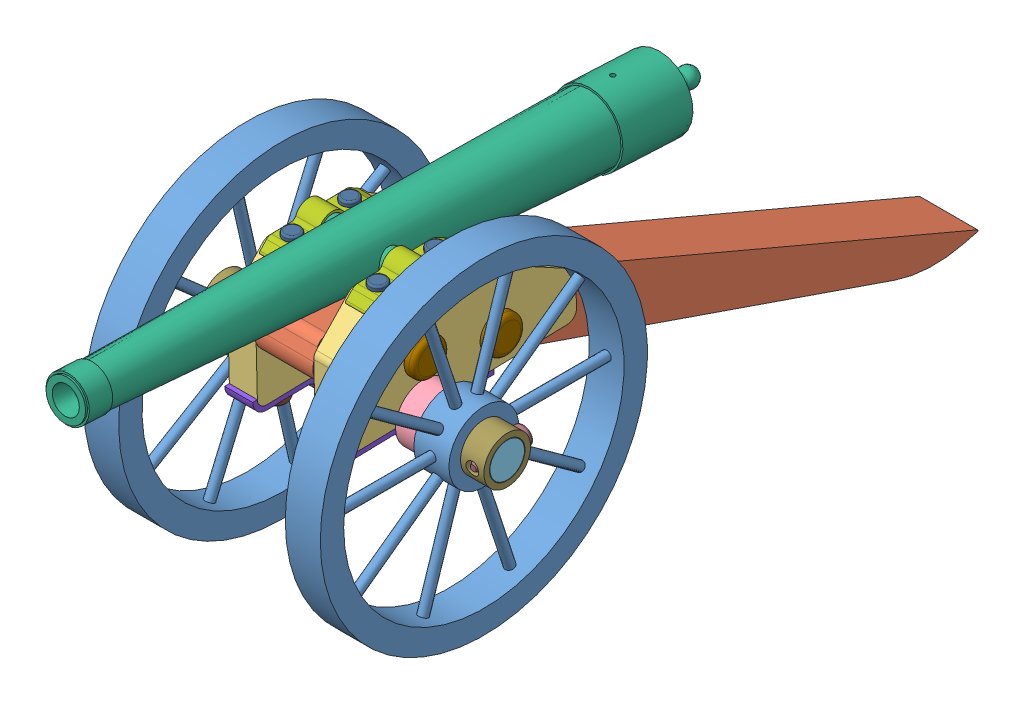
SolidWorks assembly Cannon, configuration Default. Lengths in mm.
Overall size (76.96 112.22 246.97).
32 component instances, 13 part files, 59 mates.
Components (placement in the parent):
- Wheel-1: Wheel [Default] at (68.3634 42.1628 52.5485) size (9.53 88.9 88.9)
- Wheel-2: Wheel [Default] at (13.5756 42.1628 52.5485) x (1 0 0) z (0 0.091495 0.995806) size (9.53 88.9 88.9)
- Body-1: Body [Default] at (-32.1995 -109.6773 -118.4112) x (1 0 0) z (0 0.32541 0.945573) size (30.99 51.83 194.24)
  - Tail-1: Tail [Default] at (73.3976 101.4468 142.9508) size (15.75 17.53 189.98)
  - Side-1: Side [Default] at (61.7136 98.5617 215.0109) x (-1 0 0) z (0 0.34834 -0.937368) size (7.62 31.75 63.36)
  - Side-2: Side [Default] at (85.0816 98.5617 215.0109) x (-1 0 0) z (0 0.34834 -0.937368) size (7.62 31.75 63.36)
- Shim-1: Shim [Default] at (56.7429 42.1628 52.5485) x (1 0 0) z (0 -0.052919 0.998599) size (6.35 15.24 15.24)
- Shim-2: Shim [Default] at (18.8461 42.1628 52.5485) x (1 0 0) z (0 -0.853507 -0.521081) size (6.35 15.24 15.24)
- Axle-1: Axle [Default] at (40.9949 42.1628 52.5485) x (1 0 0) z (0 -0.996928 -0.078322) size (76.96 9.4 9.4)
- Barrel-1: Barrel [Default] at (41.1981 73.9034 53.3217) x (-1 0 0) z (0 -0.049929 -0.998753) size (30.48 19.18 171.63)
- BarrelStrap-1: BarrelStrap [Default] at (52.8821 73.9034 53.3209) x (1 0 0) z (0 -0.024351 0.999703) size (6.35 6.43 27.12)
- BarrelStrap-2: BarrelStrap [Default] at (29.5141 73.9034 53.3209) x (1 0 0) z (0 -0.024351 0.999703) size (6.35 6.43 27.12)
- AxleStrap-1: AxleStrap [Default] at (29.5141 41.528 52.5328) x (1 0 0) z (0 0.024351 -0.999703) size (7.62 9.27 42.12)
- AxleStrap-2: AxleStrap [Default] at (52.8821 41.528 52.5328) x (1 0 0) z (0 0.024351 -0.999703) size (7.62 9.27 42.12)
- BodyPin-1: BodyPin [Default] at (49.7071 59.4063 67.5249) x (-1 0 0) z (0 -0.924225 -0.381849) size (16.51 9.78 9.78)
- BodyPin-2: BodyPin [Default] at (32.6891 55.8626 52.8822) size (16.51 9.78 9.78)
- BodyPin-3: BodyPin [Default] at (32.6891 59.4063 67.5249) size (16.51 9.78 9.78)
- BodyPin-4: BodyPin [Default] at (32.6891 50.8711 32.2573) size (16.51 9.78 9.78)
- BodyPin-5: BodyPin [Default] at (49.7071 55.8626 52.8822) x (-1 0 0) z (0 -0.924225 -0.381849) size (16.51 9.78 9.78)
- BodyPin-6: BodyPin [Default] at (49.7071 50.8711 32.2573) x (-1 0 0) z (0 -0.924225 -0.381849) size (16.51 9.78 9.78)
- BarrelPin-1: BarrelPin [Default] at (29.5141 69.6525 45.299) x (1 0 0) z (0 -0.024351 0.999703) size (4.57 11.43 4.57)
- BarrelPin-3: BarrelPin [Default] at (52.8821 69.6525 45.299) x (1 0 0) z (0 -0.024351 0.999703) size (4.57 11.43 4.57)
- BarrelPin-4: BarrelPin [Default] at (52.8821 69.2715 60.9421) x (1 0 0) z (0 -0.024351 0.999703) size (4.57 11.43 4.57)
- BarrelPin-5: BarrelPin [Default] at (29.5141 69.2715 60.9421) x (1 0 0) z (0 -0.024351 0.999703) size (4.57 11.43 4.57)
- AxlePin-1: AxlePin [Default] at (29.5141 46.9239 65.7034) x (-0.919486 0.009573 -0.393007) z (0 0.999703 0.024351) size (6.35 6.35 15.24)
- AxlePin-2: AxlePin [Default] at (52.8821 52.9605 65.8504) x (-0.919486 0.009573 -0.393007) z (0 0.999703 0.024351) size (6.35 6.35 15.24)
- AxlePin-3: AxlePin [Default] at (52.8821 47.5587 39.641) x (-0.919486 0.009573 -0.393007) z (0 0.999703 0.024351) size (6.35 6.35 15.24)
- AxlePin-4: AxlePin [Default] at (29.5141 47.5587 39.641) x (-0.919486 0.009573 -0.393007) z (0 0.999703 0.024351) size (6.35 6.35 15.24)
- WheelCollar-1: WheelCollar [Default] at (76.3009 42.1628 52.5485) x (1 0 0) z (0 0.078322 -0.996928) size (6.35 12.7 12.7)
- WheelCollar-2: WheelCollar [Default] at (5.6889 42.1628 52.5485) x (1 0 0) z (0 -0.078322 0.996928) size (6.35 12.7 12.7)
- WheelPin-2: WheelPin [Default] at (5.6889 42.1827 52.2953) x (0 0.996928 0.078322) z (-1 0 0) size (5.08 13.97 5.08)
- WheelPin-3: WheelPin [Default] at (76.3009 42.1827 52.2953) x (0 -0.996928 -0.078322) z (1 0 0) size (5.08 13.97 5.08)
Mates (geometry in assembly coordinates):
- Concentric1: concentric anti-aligned: cylinder of Wheel-1 through (73.1259 42.1628 52.5485) axis (-1 0 0) radius 4.7625; cylinder of Body-1/Side-2 through (49.0721 42.1628 52.5485) axis (1 0 0) radius 4.826
- Concentric2: concentric anti-aligned: cylinder of Wheel-2 through (18.3381 42.1628 52.5485) axis (-1 0 0) radius 4.7625; cylinder of Body-1/Side-1 through (25.7041 42.1628 52.5485) axis (1 0 0) radius 4.826
- Concentric3: concentric aligned: cylinder of Wheel-2 through (18.3381 42.1628 52.5485) axis (-1 0 0) radius 4.7625; cylinder of Shim-2 through (25.1961 42.1628 52.5485) axis (-1 0 0) radius 5.08
- Concentric4: concentric aligned: cylinder of Wheel-1 through (73.1259 42.1628 52.5485) axis (-1 0 0) radius 4.7625; cylinder of Shim-1 through (63.0929 42.1628 52.5485) axis (-1 0 0) radius 5.08
- Distance1: distance = 0.0508 mm anti-aligned: plane of Shim-1 through (56.7429 42.1628 52.5485) normal (-1 0 0); plane of Body-1/Side-2 through (56.6921 71.4957 47.8598) normal (1 0 0)
- Distance2: distance = 0.508 mm anti-aligned: plane of Shim-1 through (63.0929 42.1628 52.5485) normal (1 0 0); plane of Wheel-1 through (63.6009 42.1628 52.5485) normal (-1 0 0)
- Distance3: distance = 0.508 mm anti-aligned: plane of Body-1/Side-1 through (25.7041 71.4957 47.8598) normal (-1 0 0); plane of Shim-2 through (25.1961 42.1628 52.5485) normal (1 0 0)
- Distance4: distance = 0.508 mm anti-aligned: plane of Wheel-2 through (18.3381 42.1628 52.5485) normal (1 0 0); plane of Shim-2 through (18.8461 42.1628 52.5485) normal (-1 0 0)
- Concentric5: concentric aligned: cylinder of Wheel-1 through (73.1259 42.1628 52.5485) axis (-1 0 0) radius 4.7625; cylinder of Axle-1 through (79.4759 42.1628 52.5485) axis (-1 0 0) radius 4.699
- Concentric7: concentric anti-aligned: cylinder of Body-1/Side-2 through (49.0721 73.9034 53.3217) axis (1 0 0) radius 3.429; cylinder of Barrel-1 through (56.4381 73.9034 53.3217) axis (-1 0 0) radius 3.175
- Coincident2: coincident anti-aligned: plane of Body-1/Tail-1 through (41.1981 32.7657 -16.2526) normal (1 0 0); plane of Barrel-1 through (41.1981 73.9034 53.3217) normal (-1 0 0)
- Concentric8: concentric aligned: cylinder of Barrel-1 through (56.4381 73.9034 53.3217) axis (-1 0 0) radius 3.175; cylinder of BarrelStrap-1 through (56.0571 73.9034 53.3209) axis (-1 0 0) radius 3.175
- Coincident3: coincident anti-aligned: plane of Body-1/Side-2 through (49.0721 74.0349 47.9217) normal (0 0.999703 0.024351); plane of BarrelStrap-1 through (56.0571 74.0071 49.0625) normal (0 -0.999703 -0.024351)
- Concentric13: concentric anti-aligned: cylinder of Barrel-1 through (25.9581 73.9034 53.3217) axis (1 0 0) radius 3.175; cylinder of BarrelStrap-2 through (32.6891 73.9034 53.3209) axis (-1 0 0) radius 3.175
- Coincident4: coincident anti-aligned: plane of Body-1/Side-1 through (25.7041 74.0349 47.9217) normal (0 0.999703 0.024351); plane of BarrelStrap-2 through (32.6891 74.0071 49.0625) normal (0 -0.999703 -0.024351)
- Concentric18: concentric anti-aligned: cylinder of Body-1/Side-2 through (52.8821 61.0189 60.7411) axis (0 0.999703 0.024351) radius 1.5875; cylinder of BarrelStrap-1 through (52.8821 77.524 61.1431) axis (0 -0.999703 -0.024351) radius 1.6256
- Concentric19: concentric anti-aligned: cylinder of Body-1/Side-1 through (29.5141 61.0189 60.7411) axis (0 0.999703 0.024351) radius 1.5875; cylinder of BarrelStrap-2 through (29.5141 77.524 61.1431) axis (0 -0.999703 -0.024351) radius 1.6256
- Coincident5: coincident anti-aligned: plane of Body-1/Side-1 through (25.7041 43.1155 13.4362) normal (0 -0.999703 -0.024351); plane of AxleStrap-1 through (33.3241 41.6963 71.6992) normal (0 0.999703 0.024351)
- Coincident6: coincident anti-aligned: plane of Body-1/Side-2 through (49.0721 43.1155 13.4362) normal (0 -0.999703 -0.024351); plane of AxleStrap-2 through (56.6921 41.6963 71.6992) normal (0 0.999703 0.024351)
- Concentric23: concentric aligned: cylinder of Body-1/Side-2 through (52.8821 54.5416 65.8889) axis (0 -0.999703 -0.024351) radius 1.83; cylinder of AxleStrap-2 through (52.8821 44.3856 65.6415) axis (0 -0.999703 -0.024351) radius 1.6948
- Concentric24: concentric anti-aligned: cylinder of Body-1/Side-2 through (49.0721 44.2356 71.7605) axis (1 0 0) radius 2.54; cylinder of AxleStrap-2 through (56.6921 44.2356 71.7611) axis (-1 0 0) radius 2.54
- Concentric25: concentric aligned: cylinder of Body-1/Side-1 through (29.5141 54.5416 65.8889) axis (0 -0.999703 -0.024351) radius 1.83; cylinder of AxleStrap-1 through (29.5141 44.3856 65.6415) axis (0 -0.999703 -0.024351) radius 1.6948
- Concentric26: concentric anti-aligned: cylinder of Body-1/Side-1 through (25.7041 44.2356 71.7605) axis (1 0 0) radius 2.54; cylinder of AxleStrap-1 through (33.3241 44.2356 71.7611) axis (-1 0 0) radius 2.54
- Concentric27: concentric anti-aligned: cylinder of Body-1/Side-2 through (56.6921 59.4063 67.5249) axis (-1 0 0) radius 2.3813; cylinder of BodyPin-1 through (42.7221 59.4063 67.5249) axis (1 0 0) radius 2.3495
- Coincident7: coincident anti-aligned: plane of Body-1/Side-2 through (56.6921 71.4957 47.8598) normal (1 0 0); plane of BodyPin-1 through (56.6921 59.4063 67.5249) normal (-1 0 0)
- Coincident8: coincident anti-aligned: plane of Body-1/Side-2 through (56.6921 71.4957 47.8598) normal (1 0 0); plane of BodyPin-5 through (56.6921 55.8626 52.8822) normal (-1 0 0)
- Coincident9: coincident anti-aligned: plane of Body-1/Side-2 through (56.6921 71.4957 47.8598) normal (1 0 0); plane of BodyPin-6 through (56.6921 50.8711 32.2573) normal (-1 0 0)
- Concentric28: concentric anti-aligned: cylinder of Body-1/Side-2 through (56.6921 55.8626 52.8822) axis (-1 0 0) radius 2.3813; cylinder of BodyPin-5 through (42.7221 55.8626 52.8822) axis (1 0 0) radius 2.3495
- Concentric29: concentric anti-aligned: cylinder of Body-1/Side-2 through (56.6921 50.8711 32.2573) axis (-1 0 0) radius 2.3813; cylinder of BodyPin-6 through (42.7221 50.8711 32.2573) axis (1 0 0) radius 2.3495
- Concentric30: concentric aligned: cylinder of Body-1/Side-1 through (33.3241 50.8711 32.2573) axis (-1 0 0) radius 2.3813; cylinder of BodyPin-4 through (39.6741 50.8711 32.2573) axis (-1 0 0) radius 2.3495
- Concentric31: concentric aligned: cylinder of Body-1/Side-1 through (33.3241 55.8626 52.8822) axis (-1 0 0) radius 2.3813; cylinder of BodyPin-2 through (39.6741 55.8626 52.8822) axis (-1 0 0) radius 2.3495
- Concentric32: concentric aligned: cylinder of Body-1/Side-1 through (33.3241 59.4063 67.5249) axis (-1 0 0) radius 2.3813; cylinder of BodyPin-3 through (39.6741 59.4063 67.5249) axis (-1 0 0) radius 2.3495
- Coincident10: coincident anti-aligned: plane of Body-1/Side-1 through (25.7041 71.4957 47.8598) normal (-1 0 0); plane of BodyPin-3 through (25.7041 59.4063 67.5249) normal (1 0 0)
- Coincident11: coincident anti-aligned: plane of Body-1/Side-1 through (25.7041 71.4957 47.8598) normal (-1 0 0); plane of BodyPin-2 through (25.7041 55.8626 52.8822) normal (1 0 0)
- Coincident12: coincident anti-aligned: plane of Body-1/Side-1 through (25.7041 71.4957 47.8598) normal (-1 0 0); plane of BodyPin-4 through (25.7041 50.8711 32.2573) normal (1 0 0)
- Coincident13: coincident anti-aligned: plane of BarrelStrap-2 through (32.6891 74.7856 43.1794) normal (0 0.999703 0.024351); plane of BarrelPin-1 through (29.5141 74.731 45.4227) normal (0 -0.999703 -0.024351)
- Concentric34: concentric anti-aligned: cylinder of Body-1/Side-1 through (29.5141 61.3999 45.098) axis (0 0.999703 0.024351) radius 1.5875; cylinder of BarrelPin-1 through (29.5141 74.731 45.4227) axis (0 -0.999703 -0.024351) radius 1.524
- Concentric35: concentric anti-aligned: cylinder of Body-1/Side-1 through (29.5141 61.0189 60.7411) axis (0 0.999703 0.024351) radius 1.5875; cylinder of BarrelPin-5 through (29.5141 74.3499 61.0658) axis (0 -0.999703 -0.024351) radius 1.524
- Concentric36: concentric anti-aligned: cylinder of Body-1/Side-2 through (52.8821 61.0189 60.7411) axis (0 0.999703 0.024351) radius 1.5875; cylinder of BarrelPin-4 through (52.8821 74.3499 61.0658) axis (0 -0.999703 -0.024351) radius 1.524
- Concentric37: concentric anti-aligned: cylinder of Body-1/Side-2 through (52.8821 61.3999 45.098) axis (0 0.999703 0.024351) radius 1.5875; cylinder of BarrelPin-3 through (52.8821 74.731 45.4227) axis (0 -0.999703 -0.024351) radius 1.524
- Coincident14: coincident anti-aligned: plane of BarrelStrap-1 through (56.0571 74.7856 43.1794) normal (0 0.999703 0.024351); plane of BarrelPin-3 through (52.8821 74.731 45.4227) normal (0 -0.999703 -0.024351)
- Coincident15: coincident anti-aligned: plane of BarrelStrap-1 through (56.0571 74.2908 63.4933) normal (0 0.999703 0.024351); plane of BarrelPin-4 through (52.8821 74.3499 61.0658) normal (0 -0.999703 -0.024351)
- Coincident16: coincident anti-aligned: plane of BarrelStrap-2 through (32.6891 74.2908 63.4933) normal (0 0.999703 0.024351); plane of BarrelPin-5 through (29.5141 74.3499 61.0658) normal (0 -0.999703 -0.024351)
- Coincident17: coincident anti-aligned: plane of AxleStrap-1 through (33.3241 40.4267 71.6683) normal (0 -0.999703 -0.024351); plane of AxlePin-1 through (29.5141 40.5758 65.5487) normal (0 0.999703 0.024351)
- Concentric38: concentric aligned: cylinder of Body-1/Side-1 through (29.5141 54.5416 65.8889) axis (0 -0.999703 -0.024351) radius 1.83; cylinder of AxlePin-1 through (29.5141 53.272 65.858) axis (0 -0.999703 -0.024351) radius 1.8034
- Concentric39: concentric aligned: cylinder of Body-1/Side-1 through (29.5141 55.1765 39.8266) axis (0 -0.999703 -0.024351) radius 1.8592; cylinder of AxlePin-4 through (29.5141 53.9068 39.7957) axis (0 -0.999703 -0.024351) radius 1.8034
- Concentric40: concentric aligned: cylinder of Body-1/Side-2 through (52.8821 54.5416 65.8889) axis (0 -0.999703 -0.024351) radius 1.83; cylinder of AxlePin-2 through (52.8821 59.3086 66.005) axis (0 -0.999703 -0.024351) radius 1.8034
- Concentric41: concentric aligned: cylinder of Body-1/Side-2 through (52.8821 55.1765 39.8266) axis (0 -0.999703 -0.024351) radius 1.8592; cylinder of AxlePin-3 through (52.8821 53.9068 39.7957) axis (0 -0.999703 -0.024351) radius 1.8034
- Coincident18: coincident anti-aligned: plane of AxleStrap-2 through (56.6921 40.4267 71.6683) normal (0 -0.999703 -0.024351); plane of AxlePin-4 through (29.5141 41.2106 39.4864) normal (0 0.999703 0.024351)
- Coincident19: coincident anti-aligned: plane of AxleStrap-2 through (56.6921 41.0888 44.4885) normal (0 -0.999703 -0.024351); plane of AxlePin-3 through (52.8821 41.2106 39.4864) normal (0 0.999703 0.024351)
- Concentric42: concentric aligned: cylinder of Axle-1 through (5.6889 42.5308 47.8639) axis (0 -0.078322 0.996928) radius 1.5875; cylinder of WheelCollar-2 through (5.6889 42.6602 46.218) axis (0 -0.078322 0.996928) radius 1.7145
- Concentric43: concentric aligned: cylinder of Axle-1 through (79.4759 42.1628 52.5485) axis (-1 0 0) radius 4.699; cylinder of WheelCollar-2 through (8.8639 42.1628 52.5485) axis (-1 0 0) radius 4.826
- Concentric45: concentric anti-aligned: cylinder of Axle-1 through (76.3009 42.5308 47.8639) axis (0 -0.078322 0.996928) radius 1.5875; cylinder of WheelCollar-1 through (76.3009 41.6655 58.879) axis (0 0.078322 -0.996928) radius 1.7145
- Concentric46: concentric aligned: cylinder of Axle-1 through (79.4759 42.1628 52.5485) axis (-1 0 0) radius 4.699; cylinder of WheelCollar-1 through (79.4759 42.1628 52.5485) axis (-1 0 0) radius 4.826
- Coincident20: coincident anti-aligned: plane of Wheel-1 through (73.1259 42.1628 52.5485) normal (1 0 0); plane of WheelCollar-1 through (73.1259 42.1628 52.5485) normal (-1 0 0)
- Concentric47: concentric aligned: cylinder of Axle-1 through (5.6889 42.5308 47.8639) axis (0 -0.078322 0.996928) radius 1.5875; cylinder of WheelPin-2 through (5.6889 42.6801 45.9648) axis (0 -0.078322 0.996928) radius 1.524
- Concentric48: concentric aligned: cylinder of Axle-1 through (76.3009 42.5308 47.8639) axis (0 -0.078322 0.996928) radius 1.5875; cylinder of WheelPin-3 through (76.3009 42.6801 45.9648) axis (0 -0.078322 0.996928) radius 1.524
- Concentric49: concentric aligned: cylinder of WheelCollar-1 through (79.4759 42.1628 52.5485) axis (-1 0 0) radius 6.35; cylinder of WheelPin-3 through (78.8419 42.1628 52.5485) axis (-1 0 0) radius 6.35
- Concentric50: concentric anti-aligned: cylinder of WheelCollar-2 through (8.8639 42.1628 52.5485) axis (-1 0 0) radius 6.35; cylinder of WheelPin-2 through (3.1479 42.1628 52.5485) axis (1 0 0) radius 6.35
